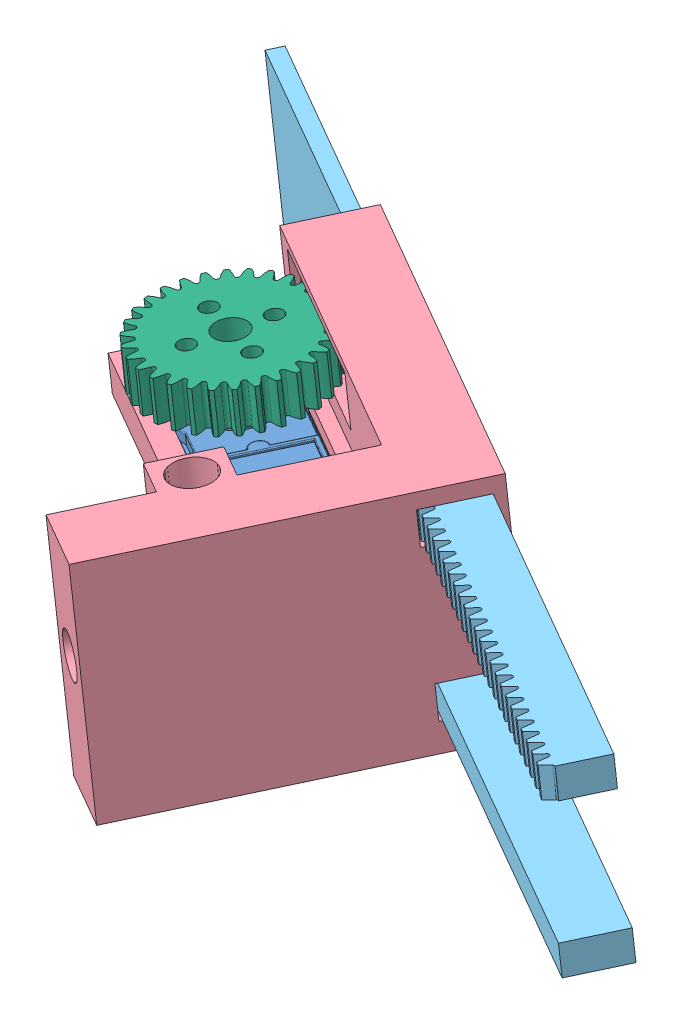
SolidWorks assembly 舵机, configuration 默认. Lengths in mm.
Overall size (179.57 60.81 120.98).
6 component instances, 6 part files, 15 mates.
Components (placement in the parent):
- Case-1: Case [默认] at (-14.3522 60.6251 120.7003) x (0.853156 0.060702 0.518112) z (-0.513574 -0.076421 0.854635)
- Output Shaft-1: Output Shaft [默认] at (-24.2273 70.4313 115.6429) x (0.955616 0.078121 0.284069) z (-0.280055 -0.058499 0.9582)
- Servo Horns-1: Servo Horns [默认] at (-25.7229 86.7033 116.1992) x (-0.446368 -0.071521 0.891987) z (0.890162 0.066405 0.45078)
- 1曲面实体-1: 1曲面实体 [默认] at (11.9191 219.9174 146.4999) x (-0.853156 -0.060702 -0.518112) z (0.513574 0.076421 -0.854635)
- 国家标准GB_齿条 GB_T1356-2001 1 200 10 10-1: 国家标准GB_齿条 GB_T1356-2001 1 200 10 10 [默认] at (-73.2928 78.7956 58.2389) x (0.853156 0.060702 0.518112) z (-0.513574 -0.076421 0.854635)
- 国家标准GB_GB_T1356-2001 1 30 20 8 22-1: 国家标准GB_GB_T1356-2001 1 30 20 8 22 [默认] at (-26.194 91.8287 116.3745) x (-0.943163 -0.075624 -0.323613) z (-0.319495 -0.061692 0.945578)
Mates (geometry in assembly coordinates):
- 同心1: concentric aligned: cylinder of Case-1 through (-21.6074 41.9264 114.6684) axis (-0.091473 0.995226 0.034024) radius 3.25; cylinder of Output Shaft-1 through (-24.7316 75.9179 115.8305) axis (-0.091473 0.995226 0.034024) radius 3
- 距离1: distance = 4.8407 mm aligned: plane of Output Shaft-1 through (-23.9454 85.6955 116.6572) normal (-0.091473 0.995226 0.034024); plane of Case-1 through (-25.1749 80.7412 115.9954) normal (-0.091473 0.995226 0.034024)
- 齿轮配合1: gear = 1 : 1 mm: line of Servo Horns-1 through (-27.9778 82.1155 116.4822) axis (-0.091473 0.995226 0.034024); line of Output Shaft-1 through (-28.0245 84.9892 114.5939) axis (0.091473 -0.995226 -0.034024)
- 同心2: concentric aligned: cylinder of Output Shaft-1 through (-24.7316 75.9179 115.8305) axis (-0.091473 0.995226 0.034024) radius 1.5; cylinder of Servo Horns-1 through (-25.6177 85.5588 116.1601) axis (-0.091473 0.995226 0.034024) radius 1.5
- 重合4: coincident anti-aligned: plane of Output Shaft-1 through (-23.9454 85.6955 116.6572) normal (-0.091473 0.995226 0.034024); plane of Servo Horns-1 through (-25.6177 85.5588 116.1601) normal (0.091473 -0.995226 -0.034024)
- 重合9: coincident anti-aligned: plane of Case-1 through (2.5315 72.6966 140.7013) normal (-0.091473 0.995226 0.034024); plane of 1曲面实体-1 through (17.8793 74.5862 126.6914) normal (0.091473 -0.995226 -0.034024)
- 平行2: parallel aligned: plane of Case-1 through (-37.8177 68.2235 118.9796) normal (-0.853156 -0.060702 -0.518112); plane of 1曲面实体-1 through (-35.0164 70.8227 94.5684) normal (-0.853156 -0.060702 -0.518112)
- 重合14: coincident anti-aligned: plane of Case-1 through (-3.5457 77.4737 140.4017) normal (0.853156 0.060702 0.518112); plane of 1曲面实体-1 through (-1.2482 50.7787 139.7463) normal (-0.853156 -0.060702 -0.518112)
- 相切1: tangent anti-aligned: cylinder of Case-1 through (-20.8525 33.7135 114.3877) axis (-0.091473 0.995226 0.034024) radius 10; plane of 1曲面实体-1 through (9.1773 52.3301 122.3972) normal (-0.513574 -0.076421 0.854635)
- 平行4: parallel anti-aligned: plane of 1曲面实体-1 through (-56.597 89.8826 81.5492) normal (0.091473 -0.995226 -0.034024); plane of 国家标准GB_齿条 GB_T1356-2001 1 200 10 10-1 through (-74.2075 88.7478 58.5792) normal (-0.091473 0.995226 0.034024)
- 平行5: parallel anti-aligned: plane of 1曲面实体-1 through (-50.0963 84.2925 71.4998) normal (-0.513574 -0.076421 0.854635); plane of 国家标准GB_齿条 GB_T1356-2001 1 200 10 10-1 through (-72.7792 78.872 57.3843) normal (0.513574 0.076421 -0.854635)
- 同心7: concentric aligned: cylinder of Servo Horns-1 through (-25.6177 85.5588 116.1601) axis (-0.091473 0.995226 0.034024) radius 10; cylinder of 国家标准GB_GB_T1356-2001 1 30 20 8 22-1 through (-21.9969 46.1647 114.8133) axis (-0.091473 0.995226 0.034024) radius 11
- 重合19: coincident anti-aligned: plane of Servo Horns-1 through (-25.8281 87.8478 116.2384) normal (-0.091473 0.995226 0.034024); plane of 国家标准GB_GB_T1356-2001 1 30 20 8 22-1 through (-25.8281 87.8478 116.2384) normal (0.091473 -0.995226 -0.034024)
- 距离3: distance = 0.3 mm anti-aligned: plane of 国家标准GB_齿条 GB_T1356-2001 1 200 10 10-1 through (-74.2075 88.7478 58.5792) normal (-0.091473 0.995226 0.034024); plane of 1曲面实体-1 through (-56.597 89.8826 81.5492) normal (0.091473 -0.995226 -0.034024)
- 重合20: coincident anti-aligned: plane of 1曲面实体-1 through (-50.0963 84.2925 71.4998) normal (-0.513574 -0.076421 0.854635); plane of 国家标准GB_齿条 GB_T1356-2001 1 200 10 10-1 through (-72.7792 78.872 57.3843) normal (0.513574 0.076421 -0.854635)
